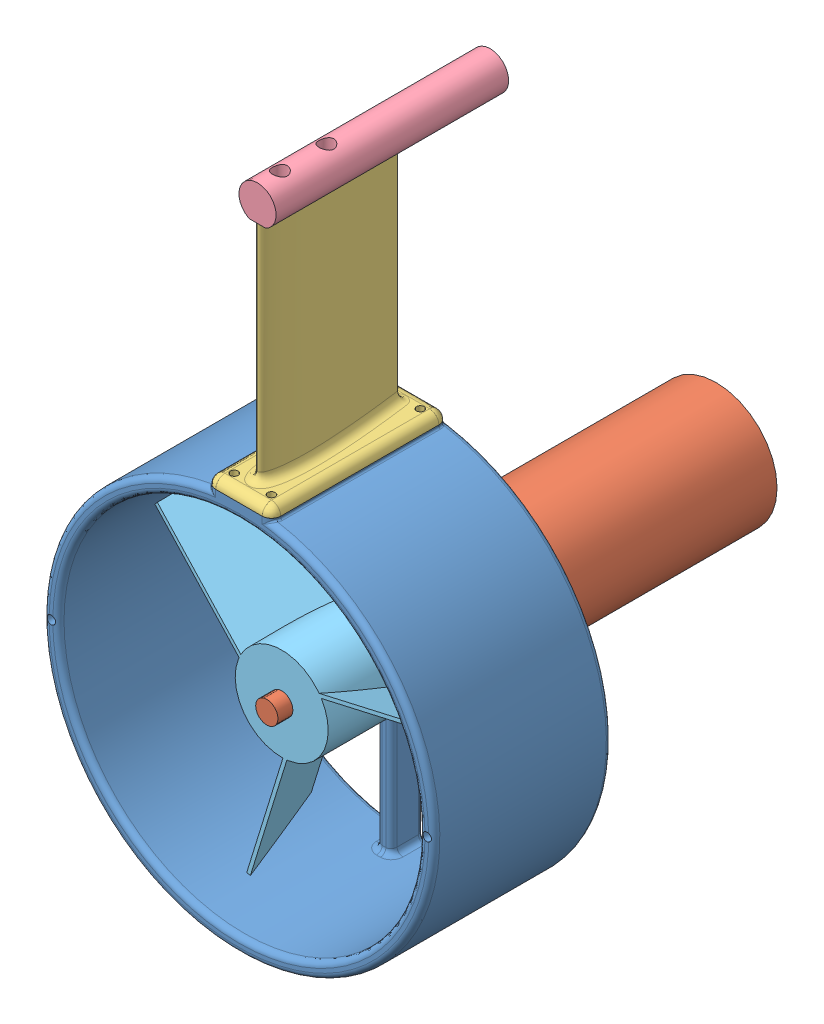
SolidWorks assembly duct assembly, configuration Default. Lengths in mm.
Overall size (210.34 359.25 256.86).
5 component instances, 5 part files, 15 mates.
Components (placement in the parent):
- duct-1: duct [Default] at (43.8289 77.1171 122.3444) size (210 210 95.65)
- Flipsky 65161 Motor-1: Flipsky 65161 Motor [Default] at (43.8289 77.1171 41.5944) size (65.5 65.5 241.5)
- mast - naca 0012-1: mast - naca 0012 [Default] at (43.8289 244.6171 207.3444) x (0 0 -1) z (1 0 0) size (95.94 125 35)
- bulb-1: bulb [Default] at (43.8289 316.0474 144.8444) x (-1 0 0) z (0 0 1) size (20 18.93 125)
- prop-1: prop [Default] at (43.8289 77.1171 144.3444) x (-0.295013 -0.955493 0) z (-0.955493 0.295013 0) size (143.38 50 164.92)
Mates (geometry in assembly coordinates):
- Coincident1: coincident: plane of duct-1 through (43.8289 77.1171 122.3444) normal (0 0 -1); plane of ? through (43.8289 77.1171 122.3444) normal (0 0 1)
- Concentric1: concentric: circle of duct-1; circle of ?
- Concentric2: concentric: circle of duct-1; circle of ?
- Coincident2: coincident: plane of duct-1 through (43.8289 77.1171 124.3444) normal (0 0 1); plane of ? through (43.8289 77.1171 124.3444) normal (0 0 -1)
- Concentric3: concentric: circle of duct-1; circle of ?
- Coincident3: coincident: plane of duct-1 through (43.8289 77.1171 122.3444) normal (0 0 -1); plane of Flipsky 65161 Motor-1 through (43.8289 77.1171 122.3444) normal (0 0 1)
- Concentric4: concentric: circle of duct-1; circle of Flipsky 65161 Motor-1
- Concentric9: concentric: circle of Flipsky 65161 Motor-1; circle of prop-1
- Distance1: distance = 8 mm: plane of prop-1 through (43.8289 77.1171 194.3444) normal (0 0 1); plane of Flipsky 65161 Motor-1 through (43.8289 77.1171 202.3444) normal (0 0 1)
- Coincident4: coincident: plane of duct-1 through (31.3289 182.1171 212.3444) normal (0 1 0); plane of mast - naca 0012-1 through (43.634 182.1171 207.3172) normal (0 -1 0)
- Concentric11: concentric: circle of duct-1; circle of mast - naca 0012-1
- Concentric12: concentric: circle of duct-1; circle of mast - naca 0012-1
- Coincident5: coincident: plane of mast - naca 0012-1 through (43.634 307.1171 207.3172) normal (0 1 0); plane of bulb-1 through (48.3289 307.1171 82.3444) normal (0 -1 0)
- Concentric13: concentric: circle of mast - naca 0012-1; circle of bulb-1
- Concentric14: concentric: circle of mast - naca 0012-1; circle of bulb-1
